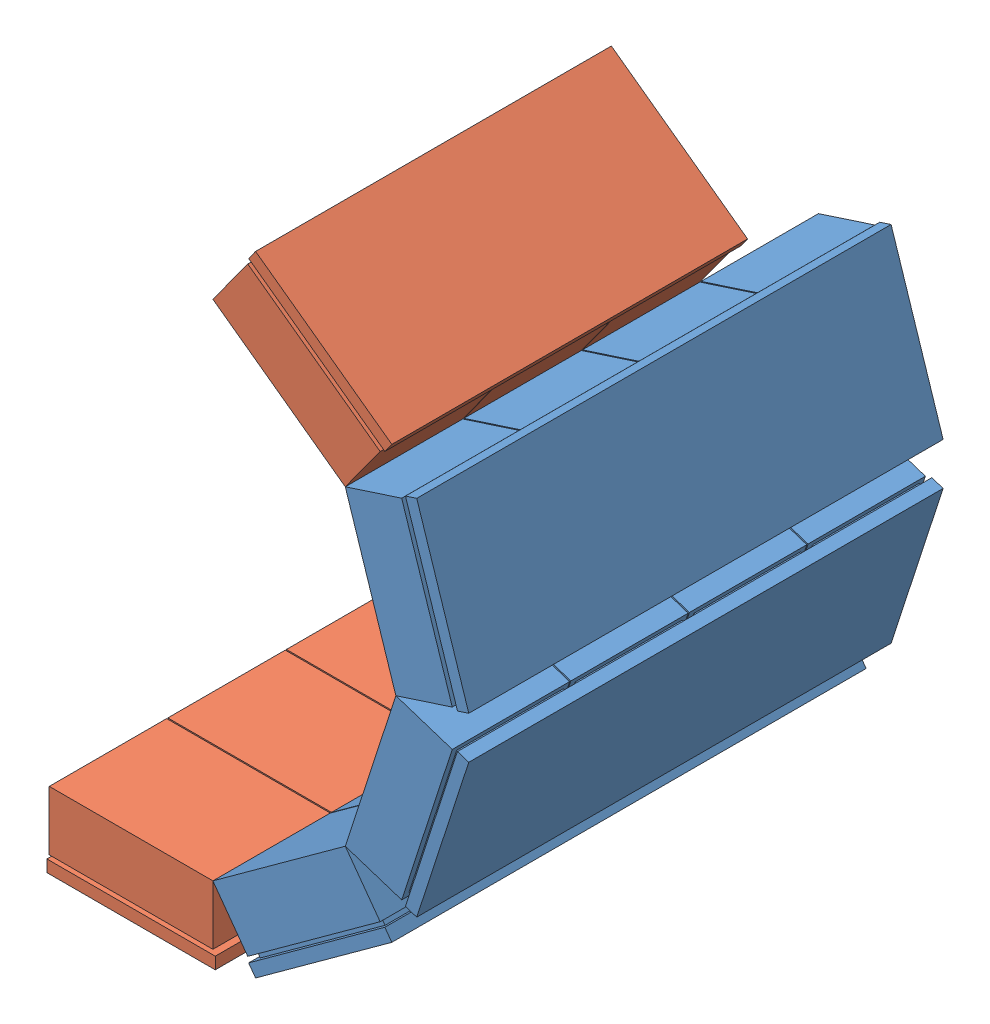
SolidWorks assembly CshapedDetector2, configuration Default. Lengths in mm.
Overall size (177.89 270.84 200).
5 component instances, 2 part files, 20 mates.
Components (placement in the parent):
- 1Detector-2: 1Detector [Default] at (173.0714 153.2337 184.2598) x (0.809017 0.587785 0) z (0 0 1) size (71 32 200)
- 1Detector-4: 1Detector [Default] at (223.2683 222.3237 184.2598) x (0.309017 0.951057 0) z (0 0 1) size (71 32 200)
- 1Detector-5: 1Detector [Default] at (223.2683 307.7237 184.2598) x (-0.309017 0.951057 0) z (0 0 1) size (71 32 200)
- 1Detector_3modules-1: 1Detector_3modules [Default] at (91.8512 126.8436 209.2598) size (71 32 150)
- 1Detector_3modules-2: 1Detector_3modules [Default] at (173.0714 376.8138 209.2598) x (-0.809017 0.587785 0) z (0 0 1) size (71 32 150)
Mates (geometry in assembly coordinates):
- Coincident2: coincident anti-aligned: line of ? through (126.3512 158.8436 284.2598) axis (0 0 -1); line of 1Detector-2 through (126.3512 158.8436 234.7598) axis (0 0 1)
- Parallel1: parallel anti-aligned: line of ? through (126.3512 158.8436 284.2598) axis (0 0 -1); line of 1Detector-2 through (126.3512 158.8436 234.7598) axis (0 0 1)
- Angle6: planar angle = 2.513274 rad anti-aligned: line of 1Detector-2 through (126.3512 158.8436 284.2598) axis (0.809017 0.587785 0); line of ? through (57.3512 158.8436 284.2598) axis (1 0 0)
- Coincident12: coincident: line of ? through (126.3512 158.8436 284.2598) axis (0 0 -1); plane of 1Detector-2 through (154.2623 179.1222 184.2598) normal (-0.587785 0.809017 0)
- Coincident19: coincident anti-aligned: line of 1Detector-2 through (182.1734 199.4008 284.2598) axis (0 0 -1); line of 1Detector-4 through (182.1734 199.4008 234.7598) axis (0 0 1)
- Coincident22: coincident: point of ?; point of 1Detector-2
- Angle9: planar angle = 2.513274 rad anti-aligned: line of 1Detector-4 through (182.1734 199.4008 284.2598) axis (0.309017 0.951057 0); line of 1Detector-2 through (126.3512 158.8436 284.2598) axis (0.809017 0.587785 0)
- Coincident24: coincident: point of 1Detector-2; point of 1Detector-4
- Coincident25: coincident anti-aligned: line of 1Detector-4 through (203.4956 265.0237 284.2598) axis (0 0 -1); line of 1Detector-5 through (203.4956 265.0237 234.7598) axis (0 0 1)
- Angle10: planar angle = 2.513274 rad anti-aligned: line of 1Detector-5 through (203.4956 265.0237 284.2598) axis (-0.309017 0.951057 0); line of 1Detector-4 through (182.1734 199.4008 284.2598) axis (0.309017 0.951057 0)
- Coincident27: coincident: point of 1Detector-4; point of 1Detector-5
- Coincident28: coincident anti-aligned: line of 1Detector-5 through (182.1734 330.6466 284.2598) axis (0 0 -1); line of ? through (182.1734 330.6466 234.7598) axis (0 0 1)
- Angle11: planar angle = 2.513274 rad anti-aligned: line of ? through (182.1734 330.6466 284.2598) axis (-0.809017 0.587785 0); line of 1Detector-5 through (203.4956 265.0237 284.2598) axis (-0.309017 0.951057 0)
- Coincident30: coincident: point of 1Detector-5; point of ?
- Coincident31: coincident: line of 1Detector-2 through (126.3512 158.8436 234.7598) axis (0 0 1); line of 1Detector_3modules-1 through (126.3512 158.8436 284.2598) axis (0 0 -1)
- Angle12: planar angle = 2.513274 rad anti-aligned: line of 1Detector_3modules-1 through (57.3512 158.8436 284.2598) axis (1 0 0); line of 1Detector-2 through (126.3512 158.8436 284.2598) axis (0.809017 0.587785 0)
- Coincident33: coincident: point of 1Detector-2; point of 1Detector_3modules-1
- Coincident34: coincident: line of 1Detector-5 through (182.1734 330.6466 284.2598) axis (0 0 -1); line of 1Detector_3modules-2 through (182.1734 330.6466 234.7598) axis (0 0 1)
- Angle14: planar angle = 2.513274 rad: line of 1Detector_3modules-2 through (182.1734 330.6466 284.2598) axis (-0.809017 0.587785 0); line of 1Detector-5 through (203.4956 265.0237 284.2598) axis (-0.309017 0.951057 0)
- Coincident37: coincident: point of 1Detector-5; point of 1Detector_3modules-2
